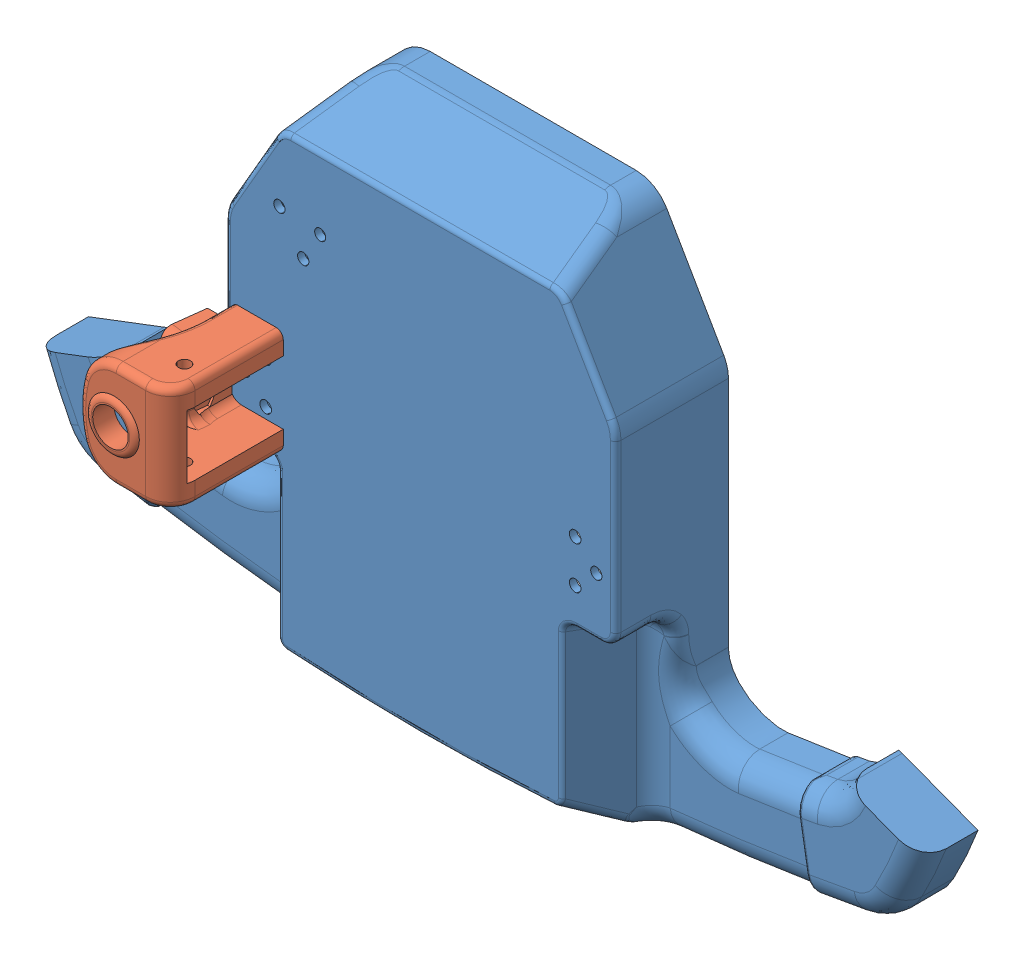
SolidWorks assembly tyl_zlozenie, configuration Default. Lengths in mm.
Overall size (252.36 146.43 65.04).
2 component instances, 2 part files, 3 mates.
Components (placement in the parent):
- tyl-1: tyl [Domyślna] at (128.0501 149.9179 145.7014) size (252.36 146.43 32.01)
- shifter_main_part_short_v2-1: shifter_main_part_short_v2 [Domyślna] at (296.0087 133.9179 109.0756) x (1 0 0) z (0 -1 0) size (35.26 33.03 30)
Mates (geometry in assembly coordinates):
- Koncentryczne1: concentric: circle of tyl-1; circle of shifter_main_part_short_v2-1
- Koncentryczne2: concentric: circle of tyl-1; circle of shifter_main_part_short_v2-1
- Wspólnie1: coincident anti-aligned: plane of tyl-1 through (128.0501 149.9179 182.7014) normal (0 0 1); plane of shifter_main_part_short_v2-1 through (296.0087 133.9179 182.7014) normal (0 0 -1)
